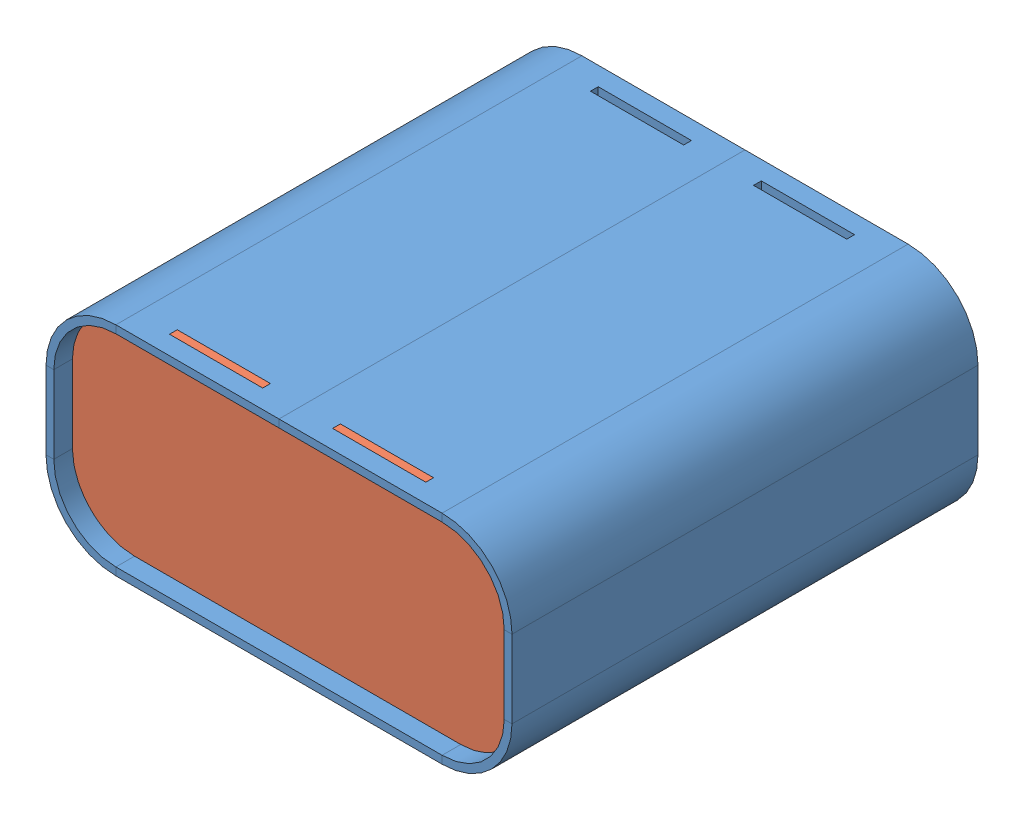
SolidWorks assembly Assem1, configuration Default. Lengths in mm.
Overall size (150 254.82 150).
2 component instances, 2 part files, 3 mates.
Components (placement in the parent):
- Part1-1: Part1 [Default] at origin size (150 254.82 150)
- Part2-1: Part2 [Default] at (0 -15 141.5) x (1 0 0) z (0 -1 0) size (145 2.5 70)
Mates (geometry in assembly coordinates):
- Coincident1: coincident: plane of Part1-1 through (-41.25 -110 141.5) normal (0 0 1); plane of Part2-1 through (52.5 -2.5 141.5) normal (0 0 -1)
- Coincident2: coincident: plane of Part1-1 through (0 20 0) normal (0 1 0); plane of Part2-1 through (-41.25 20 144) normal (0 1 0)
- Coincident3: coincident anti-aligned: plane of Part1-1 through (-41.25 -110 144) normal (1 0 0); plane of Part2-1 through (-41.25 20 144) normal (-1 0 0)
